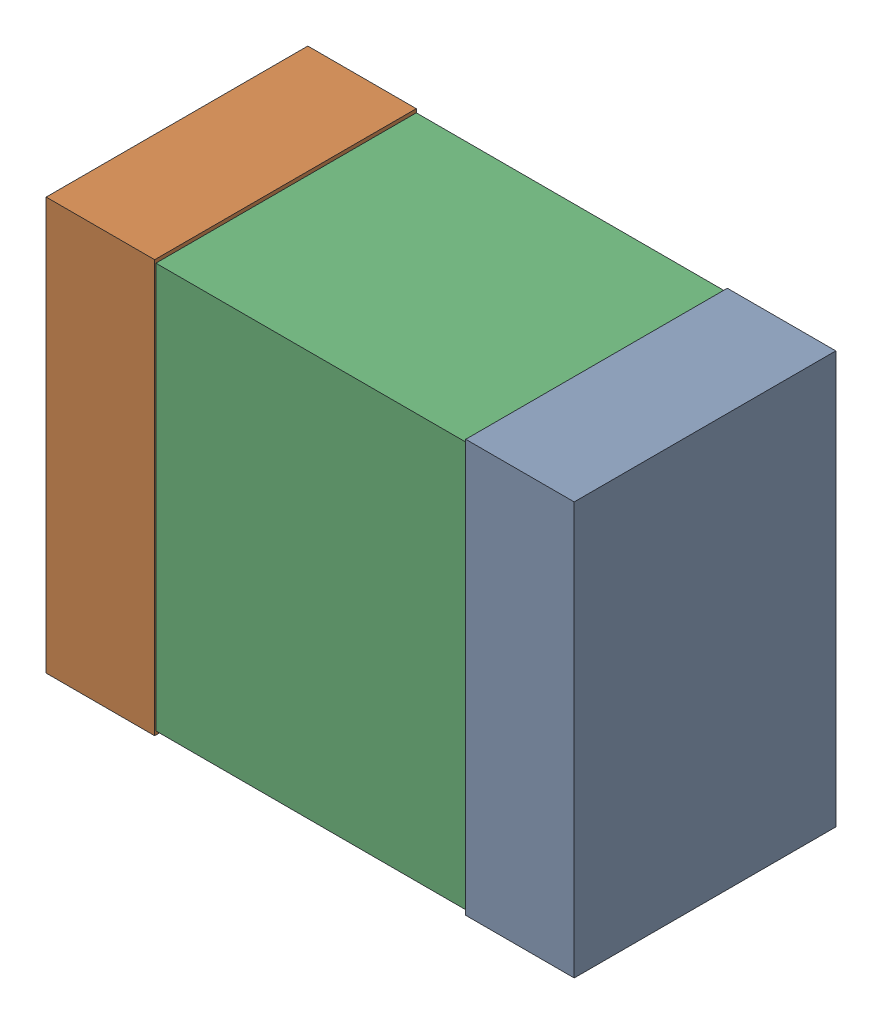
SolidWorks assembly C11_0Kanaloa_v2.0.0_Motor, configuration Default. Lengths in mm.
Overall size (3.65 2.85 1.81).
6 component instances, 2 part files, 0 mates.
Components (placement in the parent):
- 334788400-1: 334788400 [Default] at (36.248 53.086 0) size (0.75 2.85 1.81)
  - Extruded_5-1: Extruded_5 [Default] at origin size (0.75 2.85 1.81)
- 334788400-2: 334788400 [Default] at (33.348 53.086 0) size (0.75 2.85 1.81)
  - Extruded_5-1: Extruded_5 [Default] at origin size (0.75 2.85 1.81)
- 334788784-1: 334788784 [Default] at (34.798 53.086 0) size (3.6 2.8 1.8)
  - Extruded_6-1: Extruded_6 [Default] at origin size (3.6 2.8 1.8)
